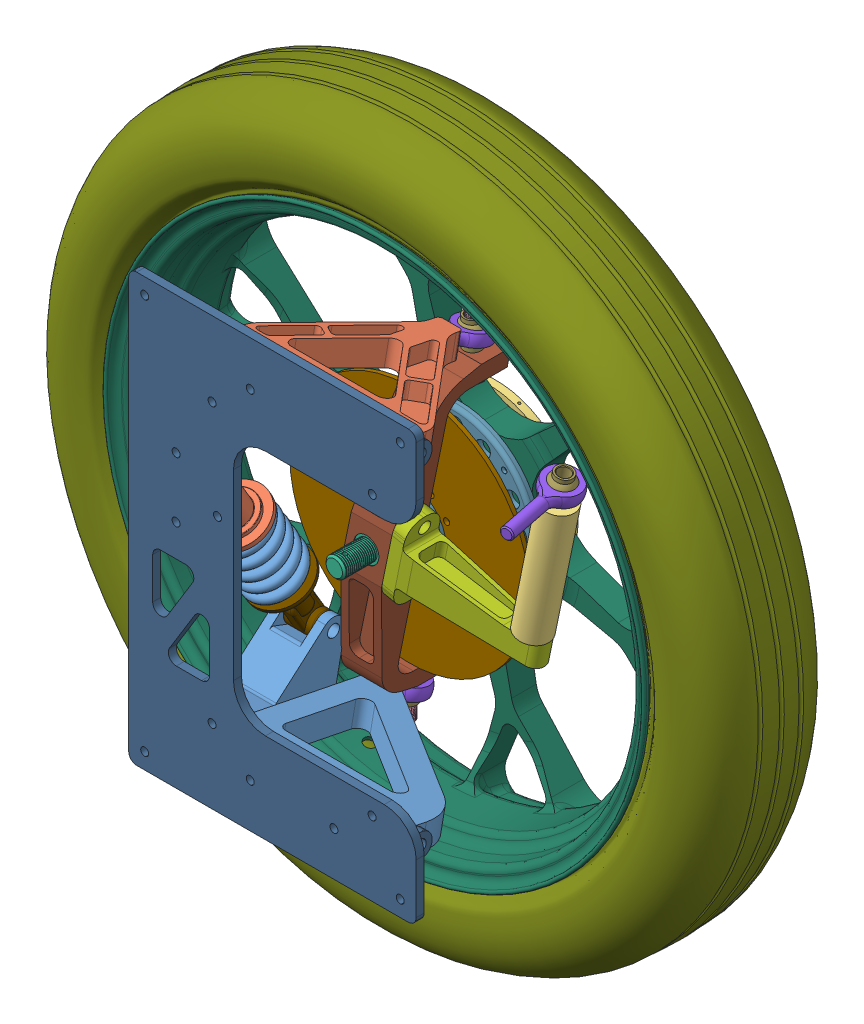
SolidWorks assembly Front Wheel Assembly, configuration Default. Lengths in mm.
Overall size (736.43 736.43 217.08).
26 component instances, 21 part files, 58 mates.
Components (placement in the parent):
- NewWishbone-1: NewWishbone [Default] at (-208.945 -92.3213 142.5637) x (1 0 0) z (0 0.196638 0.980476) size (183.89 64.96 127)
- NewWishboneTop-1: NewWishboneTop [Default] at (-199.42 176.9187 142.5637) x (1 0 0) z (0 0.196638 0.980476) size (146.05 19.05 127)
- Nut-1: Nut [Default] at (-174.02 47.8918 83.6508) x (0.981942 0.18918 0) z (0 0 1) size (130 130 15.86)
- SKF_6003-2Z.stp-1: SKF_6003-2Z.stp [Default] at (-174.02 47.8918 100.9457) x (0 0 -1) z (0.985702 -0.168499 0) size (10 35 35)
- SKF_6004-2Z.stp-1: SKF_6004-2Z.stp [Default] at (-174.02 47.8918 145.4457) x (0 0 -1) z (0.999998 -0.001926 0) size (12 42 42)
- Spindle_Light-1: Spindle_Light [Default] at (-174.0201 47.8918 152.4457) x (0 0 -1) z (0.979501 -0.20144 0) size (140.5 34 30)
- SteeringArmMount3-1: SteeringArmMount3 [Default] at (-158.1222 46.3873 152.4457) x (0 0 -1) z (0.979501 -0.20144 0) size (32.44 66.16 106.1)
- Swivel Ball Joint Rod End-1: Swivel Ball Joint Rod End [6960T231] at (-199.42 -82.9822 140.6908) x (-1 0 0) z (0 -0.980476 0.196638) size (28.57 68.26 9.89)
- BasicBrakeDisc-1: BasicBrakeDisc [Default] at (-174.02 47.8918 143.4457) x (0.999999 -0.001555 0) z (0 0 1) size (190.5 190.5 3.17)
- FrontSuspensionMountingPlate-1: FrontSuspensionMountingPlate [Default] at (-37.241 244.9178 278.0972) x (-1 0 0) z (0 0 -1) size (228.6 339.73 31.75)
- FrontSpindle-2: FrontSpindle [Default] at (-174.0201 47.8918 152.4457) x (1 0 0) z (0 0 1) size (83.21 247.02 73.5)
- Swivel Ball Joint Rod End-2: Swivel Ball Joint Rod End [6960T231] at (-148.62 186.2578 140.6908) x (-1 0 0) z (0 -0.980476 0.196638) size (28.57 68.26 9.89)
- Super-Swivel Ball Joint Ball End2-1: Super-Swivel Ball Joint Ball End2 [6960T231] at (-151.8803 182.5118 103.2437) x (0.985246 0 -0.171143) z (0 -1 0) size (20.64 20.64 22.23)
- Super-Swivel Ball Joint Ball End2-2: Super-Swivel Ball Joint Ball End2 [6960T231] at (-198.8916 -86.7282 102.97) x (0.999615 0 0.027738) z (0 -1 0) size (20.64 20.64 22.23)
- 91257A659_Zinc Yellow-Chromate Plated Hex Head Screw-2: 91257A659_Zinc Yellow-Chromate Plated Hex Head Screw [91257A659] at (-148.62 178.3843 122.0127) x (0 1 0) z (0.180681 0 0.983542) size (57.6 16.5 14.29)
- 91257A659_Zinc Yellow-Chromate Plated Hex Head Screw-3: 91257A659_Zinc Yellow-Chromate Plated Hex Head Screw [91257A659] at (-199.42 -82.6007 122.0127) x (0 -1 0) z (0.00058 0 1) size (57.6 16.5 14.29)
- Hub5-16-1: Hub5-16 [Default] at (-174.02 47.8918 125.0287) x (0.708206 0.706006 0) z (0.706006 -0.708206 0) size (130 85 130)
- rimmachined v13.2-1: rimmachined v13.2 [Default] at (-174.02 47.8918 128.7457) x (0 0 -1) z (-0.966188 -0.257837 0) size (93.59 431.57 431.57)
- Michelin Tire-1: Michelin Tire [Default] at (-174.02 47.8918 128.7457) x (0 0 -1) z (0.911284 -0.411779 0) size (101.13 556.61 556.61)
- Shock Absorber Rod_11-1: Shock Absorber Rod_11 [Default] at (-227.995 28.1327 206.2879) x (0.353558 0.474676 -0.806027) z (-0.935413 0.179413 -0.304654) size (6.35 19.21 6.35)
- Shock Anchor_11-1: Shock Anchor_11 [Default] at (-227.995 -29.8476 172.1429) x (1 0 0) z (0 0.50745 -0.861681) size (46 57.15 46)
- Shock Spring_11-1: Shock Spring_11 [Default] at (-228.2298 66.3963 229.124) x (1 0 0) z (0 0.50745 -0.861681) size (46 72.22 47.49)
- Shock Tube 1_11-1: Shock Tube 1_11 [Default] at (-227.995 95.9148 246.2053) x (1 0 0) z (0 -0.50745 0.861681) size (46 109.21 46)
- Standoff-1: Standoff [Default] at (-64.9504 35.3971 157.5898) x (0.972938 -0.20009 0.115567) z (-0.113198 0.02328 0.9933) size (25.4 101.6 25.4)
- Swivel Ball Joint Rod End-3: Swivel Ball Joint Rod End [6960T231] at (-38.9738 145.1479 176.3454) x (-0.964149 0.199376 0.175115) z (-0.202281 -0.979327 0.001288) size (28.57 68.26 9.89)
- Super-Swivel Ball Joint Ball End2-3: Super-Swivel Ball Joint Ball End2 [6960T231] at (-45.1475 146.3959 138.7715) x (0.967584 -0.198989 -0.155514) z (-0.20144 -0.979501 0) size (20.64 20.64 22.23)
Mates (geometry in assembly coordinates):
- Concentric2: concentric: cylinder of NewWishboneTop-1 through (-208.945 209.3578 255.8722) axis (1 0 0) radius 4.7625; cylinder of FrontSuspensionMountingPlate-1 through (-265.841 209.3578 255.8722) axis (1 0 0) radius 4.7625
- Distance1: distance = 0 mm: plane of NewWishboneTop-1 through (-189.895 195.5968 138.8178) normal (1 0 0); plane of FrontSuspensionMountingPlate-1 through (-189.895 244.9178 246.3472) normal (-1 0 0)
- Concentric3: concentric: cylinder of NewWishbone-1 through (-63.1563 -59.8822 255.8722) axis (-1 0 0) radius 4.7625; cylinder of FrontSuspensionMountingPlate-1 through (-265.841 -59.8822 255.8722) axis (1 0 0) radius 4.7625
- Concentric4: concentric: cylinder of NewWishboneTop-1 through (-148.62 193.7497 178.0469) axis (0 -0.196638 -0.980476) radius 4.7625; cylinder of Swivel Ball Joint Rod End-2 through (-148.62 186.2578 140.6908) axis (0 -0.196638 -0.980476) radius 4.7625
- Parallel1: parallel: plane of NewWishboneTop-1 through (-199.42 195.5968 138.8178) normal (0 0.980476 -0.196638); plane of Swivel Ball Joint Rod End-2 through (-134.3325 184.1773 107.1067) normal (0 0.980476 -0.196638)
- Coincident4: coincident: plane of NewWishboneTop-1 through (-199.42 195.5968 138.8178) normal (0 -0.196638 -0.980476); circle of Swivel Ball Joint Rod End-2
- Coincident5: coincident aligned: circle of NewWishbone-1; circle of Swivel Ball Joint Rod End-1
- Parallel2: parallel aligned: plane of NewWishbone-1 through (-208.945 -73.6432 138.8178) normal (0 0.980476 -0.196638); plane of Swivel Ball Joint Rod End-1 through (-185.1325 -85.0627 107.1067) normal (0 0.980476 -0.196638)
- Concentric5: concentric: sphere of Swivel Ball Joint Rod End-2; sphere of Super-Swivel Ball Joint Ball End2-1
- Concentric6: concentric: sphere of Swivel Ball Joint Rod End-1; sphere of Super-Swivel Ball Joint Ball End2-2
- Concentric8: concentric: circle of FrontSpindle-2; circle of Super-Swivel Ball Joint Ball End2-1
- Coincident11: coincident: plane of FrontSpindle-2 through (-132.4128 171.3993 180.9457) normal (0 1 0); plane of Super-Swivel Ball Joint Ball End2-1 through (-148.62 171.3993 122.0127) normal (0 -1 0)
- Concentric9: concentric: circle of FrontSpindle-2; circle of Super-Swivel Ball Joint Ball End2-2
- LimitAngle2: limit planar angle = 0.202828 rad aligned: plane of FrontSpindle-2 through (-183.2128 -75.6157 180.9457) normal (0.979501 -0.20144 0); plane of FrontSuspensionMountingPlate-1 through (-37.241 244.9178 271.7472) normal (1 0 0)
- Concentric10: concentric aligned: cylinder of FrontSpindle-2 through (-148.62 141.3993 122.0127) axis (0 1 0) radius 4.7625; cylinder of 91257A659_Zinc Yellow-Chromate Plated Hex Head Screw-2 through (-148.62 156.1593 122.0127) axis (0 1 0) radius 4.7625
- Coincident13: coincident anti-aligned: plane of FrontSpindle-2 through (-174.02 156.1593 107.4457) normal (0 -1 0); plane of 91257A659_Zinc Yellow-Chromate Plated Hex Head Screw-2 through (-151.3859 156.1593 129.7841) normal (0 1 0)
- Concentric11: concentric aligned: cylinder of FrontSpindle-2 through (-199.42 -45.6157 122.0127) axis (0 -1 0) radius 4.7625; cylinder of 91257A659_Zinc Yellow-Chromate Plated Hex Head Screw-3 through (-199.42 -60.3757 122.0127) axis (0 -1 0) radius 4.7625
- Coincident14: coincident anti-aligned: plane of FrontSpindle-2 through (-174.02 -60.3757 107.4457) normal (0 1 0); plane of 91257A659_Zinc Yellow-Chromate Plated Hex Head Screw-3 through (-195.2915 -60.3757 129.154) normal (0 -1 0)
- Concentric12: concentric aligned: cylinder of Spindle_Light-1 through (-174.02 47.8918 65.9457) axis (0 0 -1) radius 10; cylinder of FrontSpindle-2 through (-174.0201 47.8918 180.9457) axis (0 0 -1) radius 10
- Parallel6: parallel aligned: plane of Spindle_Light-1 through (-192.5231 32.3847 165.9457) normal (-0.979501 0.20144 0); plane of FrontSpindle-2 through (-215.6273 -75.6157 180.9457) normal (-0.979501 0.20144 0)
- Coincident17: coincident anti-aligned: plane of Spindle_Light-1 through (-172.0057 57.6868 152.4457) normal (0 0 1); plane of FrontSpindle-2 through (-174.0201 47.8918 152.4457) normal (0 0 -1)
- Concentric14: concentric aligned: cylinder of SKF_6004-2Z.stp-1 through (-174.02 47.8918 95.4457) axis (0 0 -1) radius 10; cylinder of Spindle_Light-1 through (-174.02 47.8918 65.9457) axis (0 0 -1) radius 10
- Coincident18: coincident: plane of SKF_6004-2Z.stp-1 through (-173.9941 61.3718 145.4457) normal (0 0 1); plane of Spindle_Light-1 through (-171.6028 59.6458 145.4457) normal (0 0 -1)
- Concentric15: concentric aligned: cylinder of SKF_6003-2Z.stp-1 through (-174.02 47.8918 50.9457) axis (0 0 -1) radius 8.5; cylinder of Spindle_Light-1 through (-174.02 47.8918 65.9457) axis (0 0 -1) radius 8.5
- Coincident19: coincident: plane of SKF_6004-2Z.stp-1 through (-173.9842 66.4868 133.4457) normal (0 0 -1); plane of Hub5-16-1 through (-160.5641 61.3059 136.4457) normal (0 0 1)
- Concentric16: concentric anti-aligned: cylinder of SKF_6003-2Z.stp-1 through (-174.02 47.8918 50.9457) axis (0 0 -1) radius 17.5; cylinder of Hub5-16-1 through (-174.0201 47.8918 1051.0565) axis (0 0 1) radius 17.5
- Coincident20: coincident anti-aligned: plane of SKF_6003-2Z.stp-1 through (-171.1219 64.8459 100.9457) normal (0 0 1); plane of Hub5-16-1 through (-163.0429 58.8349 100.9457) normal (0 0 -1)
- Concentric17: concentric anti-aligned: cylinder of Hub5-16-1 through (-174.0201 47.8918 1051.0565) axis (0 0 1) radius 47; cylinder of rimmachined v13.2-1 through (-174.02 47.8918 119.6457) axis (0 0 -1) radius 47.005
- Concentric18: concentric aligned: circle of Nut-1; circle of Hub-1
- Concentric22: concentric anti-aligned: cylinder of BasicBrakeDisc-1 through (-174.02 47.8918 146.6207) axis (0 0 -1) radius 28.956; cylinder of Hub5-16-1 through (-174.0201 47.8918 1051.0565) axis (0 0 1) radius 29
- Coincident23: coincident anti-aligned: plane of BasicBrakeDisc-1 through (-174.02 47.8918 143.4457) normal (0 0 -1); plane of Hub5-16-1 through (-153.4821 68.366 143.4457) normal (0 0 1)
- Concentric25: concentric anti-aligned: cylinder of BasicBrakeDisc-1 through (-203.4384 64.9376 146.6207) axis (0 0 -1) radius 2.497; cylinder of Hub5-16-1 through (-203.4384 64.9376 133.4457) axis (0 0 1) radius 2
- Coincident24: coincident anti-aligned: plane of Hub5-16-1 through (-140.7344 81.0741 106.4457) normal (0 0 -1); plane of rimmachined v13.2-1 through (-163.7066 9.2443 106.4457) normal (0 0 1)
- Tangent6: tangent anti-aligned: cylinder of Hub5-16-1 through (-188.9444 103.9388 109.9457) axis (0 0 -1) radius 3.9688; plane of rimmachined v13.2-1 through (-184.4652 102.5466 102.1457) normal (-0.966188 -0.257837 0)
- Concentric31: concentric anti-aligned: circle of Nut-1; circle of rimmachined v13.2-1
- Coincident25: coincident anti-aligned: plane of Nut-1 through (-139.6521 54.5131 83.6508) normal (0 0 1); plane of rimmachined v13.2-1 through (-153.6044 -28.6115 83.6508) normal (0 0 -1)
- Concentric32: concentric aligned: cylinder of rimmachined v13.2-1 through (-174.0201 47.8918 214.2549) axis (0 0 1) radius 192.7898; cylinder of Michelin Tire-1 through (-174.0201 47.8918 231.4686) axis (0 0 1) radius 203
- Coincident26: coincident aligned: plane of rimmachined v13.2-1 through (-174.02 47.8918 128.7457) normal (0 0 -1); plane of Michelin Tire-1 through (-174.02 47.8918 128.7457) normal (0 0 -1)
- Coincident27: coincident anti-aligned: plane of SteeringArmMount3-1 through (-158.1222 46.3873 152.4457) normal (-0.979501 0.20144 0); plane of FrontSpindle-2 through (-183.2128 -75.6157 180.9457) normal (0.979501 -0.20144 0)
- Coincident28: coincident: point of SteeringArmMount3-1; point of FrontSpindle-2
- Concentric34: concentric: cylinder of Shock Absorber Rod_11-1 through (-227.995 11.5764 196.5377) axis (0 0.861681 0.50745) radius 3.175; cylinder of Shock Tube 1_11-1 through (-227.995 50.0194 219.1771) axis (0 -0.861681 -0.50745) radius 3.175
- Coincident29: coincident anti-aligned: plane of Shock Anchor_11-1 through (-227.995 11.19 196.3102) normal (0 0.861681 0.50745); plane of Shock Spring_11-1 through (-228.2298 11.0578 196.5347) normal (0 -0.861681 -0.50745)
- Lock1: lock: unknown of Shock Anchor_11-1; unknown of Shock Spring_11-1
- Concentric35: concentric: cylinder of Shock Anchor_11-1 through (-227.995 -18.9042 178.5875) axis (0 -0.861681 -0.50745) radius 8.6614; cylinder of Shock Tube 1_11-1 through (-227.995 66.9149 229.127) axis (0 0.861681 0.50745) radius 11.43
- Concentric36: concentric: cylinder of NewWishbone-1 through (-247.045 -29.8476 172.1429) axis (1 0 0) radius 4.7625; cylinder of Shock Anchor_11-1 through (-221.645 -29.8476 172.1429) axis (-1 0 0) radius 5
- Coincident31: coincident: plane of NewWishbone-1 through (-240.06 -92.3213 142.5637) normal (1 0 0); plane of Shock Anchor_11-1 through (-240.06 -29.8476 172.1429) normal (-1 0 0)
- Concentric37: concentric: cylinder of FrontSuspensionMountingPlate-1 through (-265.841 112.3298 255.8722) axis (1 0 0) radius 4.7625; cylinder of Shock Tube 1_11-1 through (-215.93 112.3298 255.8722) axis (-1 0 0) radius 4.9166
- Coincident32: coincident: circle of Shock Absorber Rod_11-1; circle of Shock Tube 1_11-1
- Coincident33: coincident anti-aligned: line of SteeringArmMount3-1 through (-153.6771 68.0019 180.9457) axis (-0.20144 -0.979501 0); line of FrontSpindle-2 through (-161.9486 27.7818 180.9457) axis (0.20144 0.979501 0)
- Concentric38: concentric anti-aligned: cylinder of SteeringArmMount3-1 through (-72.6253 -1.9219 157.5898) axis (0.20144 0.979501 0) radius 4.7625; cylinder of Standoff-1 through (-44.4841 134.9144 157.5898) axis (-0.20144 -0.979501 0) radius 4.7625
- Distance4: distance = 0 mm anti-aligned: plane of Standoff-1 through (-64.9504 35.3971 157.5898) normal (-0.20144 -0.979501 0); plane of SteeringArmMount3-1 through (-156.51 54.2268 148.5086) normal (0.20144 0.979501 0)
- Concentric40: concentric aligned: cylinder of Standoff-1 through (-44.4841 134.9144 157.5898) axis (-0.20144 -0.979501 0) radius 4.7625; cylinder of Super-Swivel Ball Joint Ball End2-3 through (-40.167 155.9063 157.5898) axis (-0.20144 -0.979501 0) radius 4.7625
- Coincident35: coincident anti-aligned: plane of Standoff-1 through (-44.4841 134.9144 157.5898) normal (0.20144 0.979501 0); plane of Super-Swivel Ball Joint Ball End2-3 through (-44.4841 134.9144 157.5898) normal (-0.20144 -0.979501 0)
- Concentric41: concentric: sphere of Swivel Ball Joint Rod End-3; sphere of Super-Swivel Ball Joint Ball End2-3
- Lock2: lock: unknown of BasicBrakeDisc-1; unknown of FrontSpindle-2
- Parallel16: parallel: plane of NewWishbone-1 through (-208.945 -73.6432 138.8178) normal (0 0.980476 -0.196638); plane of NewWishboneTop-1 through (-199.42 176.9187 142.5637) normal (0 -0.980476 0.196638)
- LimitAngle6: limit planar angle = 0.001548 rad aligned: plane of Swivel Ball Joint Rod End-3 through (-30.001 147.9086 141.0152) normal (0.202281 0.979327 -0.001288); plane of Standoff-1 through (-44.4841 134.9144 157.5898) normal (0.20144 0.979501 0)
- Distance5: distance = 64.67 mm: plane of Shock Tube 1_11-1 through (-227.995 66.9149 229.127) normal (0 -0.861681 -0.50745); plane of Shock Anchor_11-1 through (-227.995 11.19 196.3102) normal (0 0.861681 0.50745)
